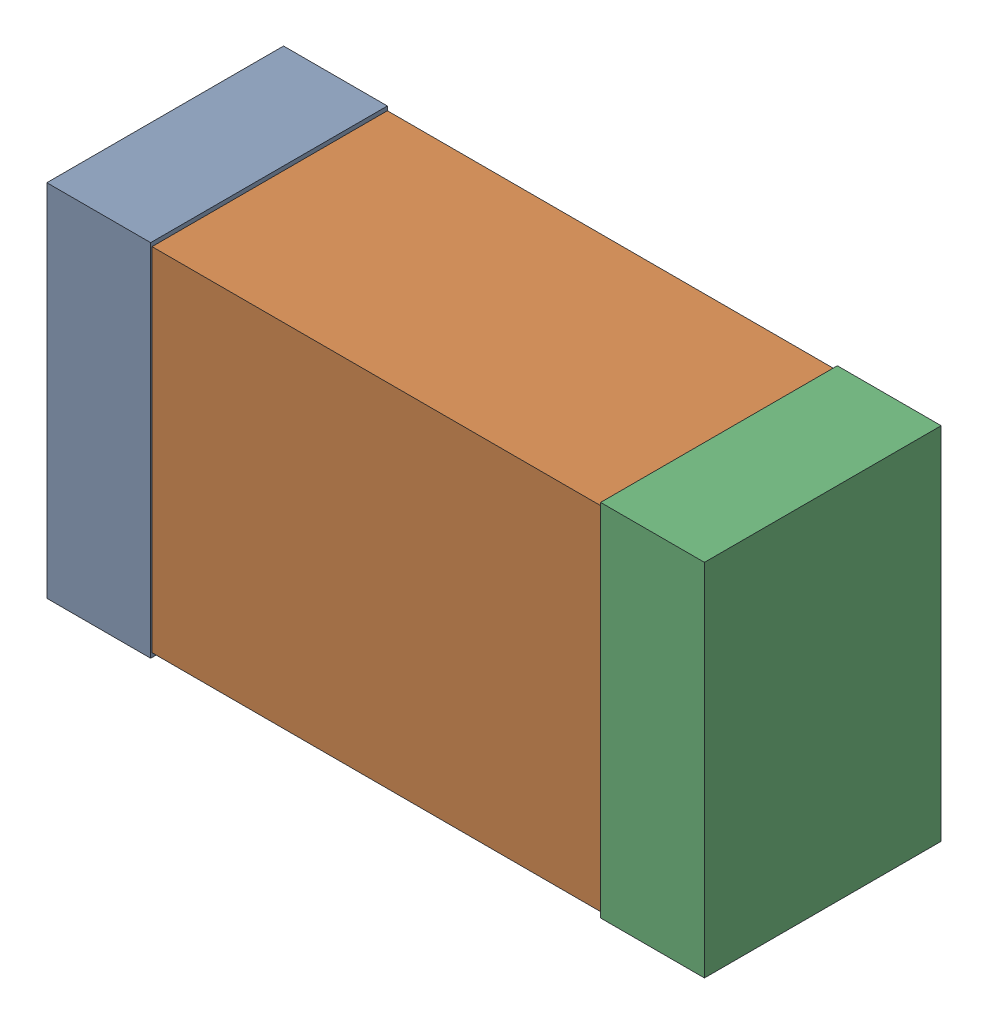
SolidWorks assembly R3_Motor_4Kanaloa_v2.0.0_Motor, configuration Default. Lengths in mm.
Overall size (2.38 1.3 0.85).
6 component instances, 2 part files, 0 mates.
Components (placement in the parent):
- 352877648-1: 352877648 [Default] at (84.403 92.964 0) size (0.38 1.3 0.85)
  - Extruded_14-1: Extruded_14 [Default] at origin size (0.38 1.3 0.85)
- 352877392-1: 352877392 [Default] at (85.403 92.964 0) size (2.2 1.27 0.85)
  - Extruded_15-1: Extruded_15 [Default] at origin size (2.2 1.27 0.85)
- 352877648-2: 352877648 [Default] at (86.403 92.964 0) size (0.38 1.3 0.85)
  - Extruded_14-1: Extruded_14 [Default] at origin size (0.38 1.3 0.85)
